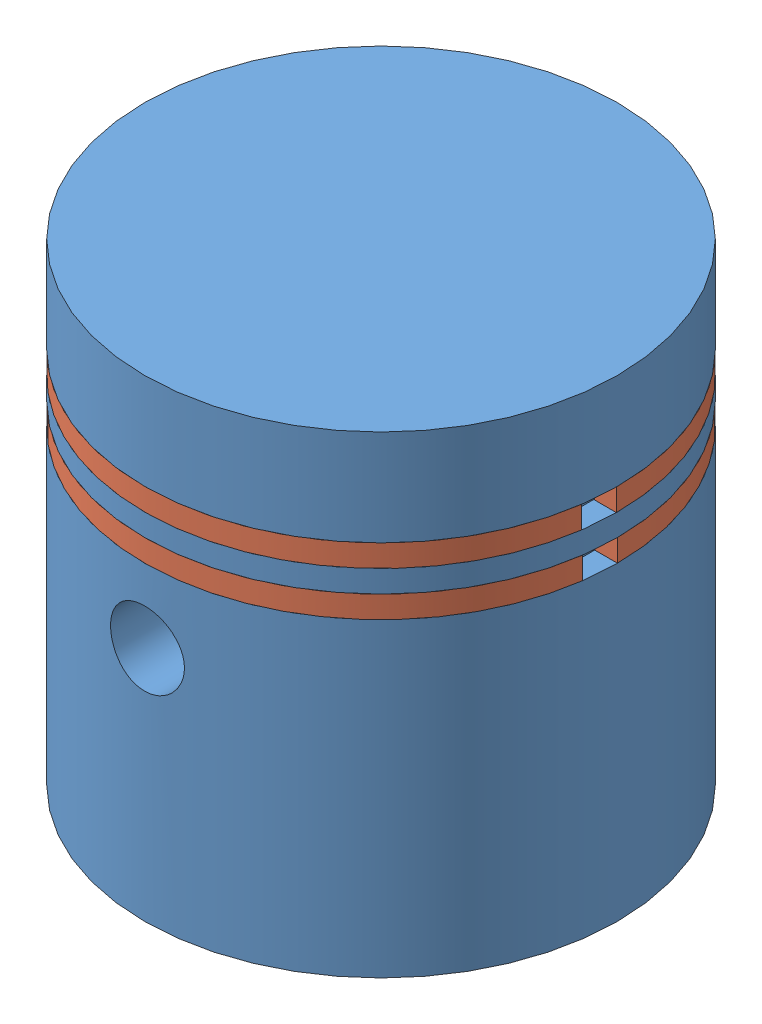
SolidWorks assembly Assembly Piston, configuration Default. Lengths in mm.
Overall size (16.07 16 16.07).
3 component instances, 2 part files, 6 mates.
Components (placement in the parent):
- Piston-1: Piston [Default] at (4.1571 -0.3575 13.7197) size (16 16 16)
- Piston Compression String-1: Piston Compression String [Default] at (11.782 12.0175 13.7545) x (-0.004553 0 0.99999) z (-0.99999 0 -0.004553) size (16 0.75 16)
- Piston Compression String-2: Piston Compression String [Default] at (11.7821 10.5175 13.7197) x (0 0 1) z (-1 0 0) size (16 0.75 16)
Mates (geometry in assembly coordinates):
- Coincident7: coincident: line of assembly; line of assembly; axis of Piston-1 through (4.1571 15.6425 13.7197) axis (0 -1 0); axis of Piston Compression String-1 through (4.1571 11.6425 13.7197) axis (0 1 0)
- Coincident8: coincident: line of assembly; line of assembly; axis of Piston-1 through (4.1571 15.6425 13.7197) axis (0 -1 0); axis of Piston Compression String-2 through (4.1571 10.1425 13.7197) axis (0 1 0)
- Coincident9: coincident: plane of Piston-1 through (4.1571 12.3925 13.7197) normal (0 -1 0); plane of Piston Compression String-1 through (11.407 12.3925 13.7528) normal (0 1 0)
- Coincident10: coincident: plane of Piston-1 through (4.1571 10.8925 13.7197) normal (0 -1 0); plane of Piston Compression String-2 through (11.4071 10.8925 13.7197) normal (0 1 0)
- Concentric14: concentric anti-aligned: cylinder of Piston-1 through (4.1571 12.3925 13.7197) axis (0 -1 0) radius 7.25; cylinder of Piston Compression String-1 through (4.1571 12.0175 13.7197) axis (0 1 0) radius 7.25
- Concentric15: concentric anti-aligned: cylinder of Piston-1 through (4.1571 10.8925 13.7197) axis (0 -1 0) radius 7.25; cylinder of Piston Compression String-2 through (4.1571 10.5175 13.7197) axis (0 1 0) radius 7.25
